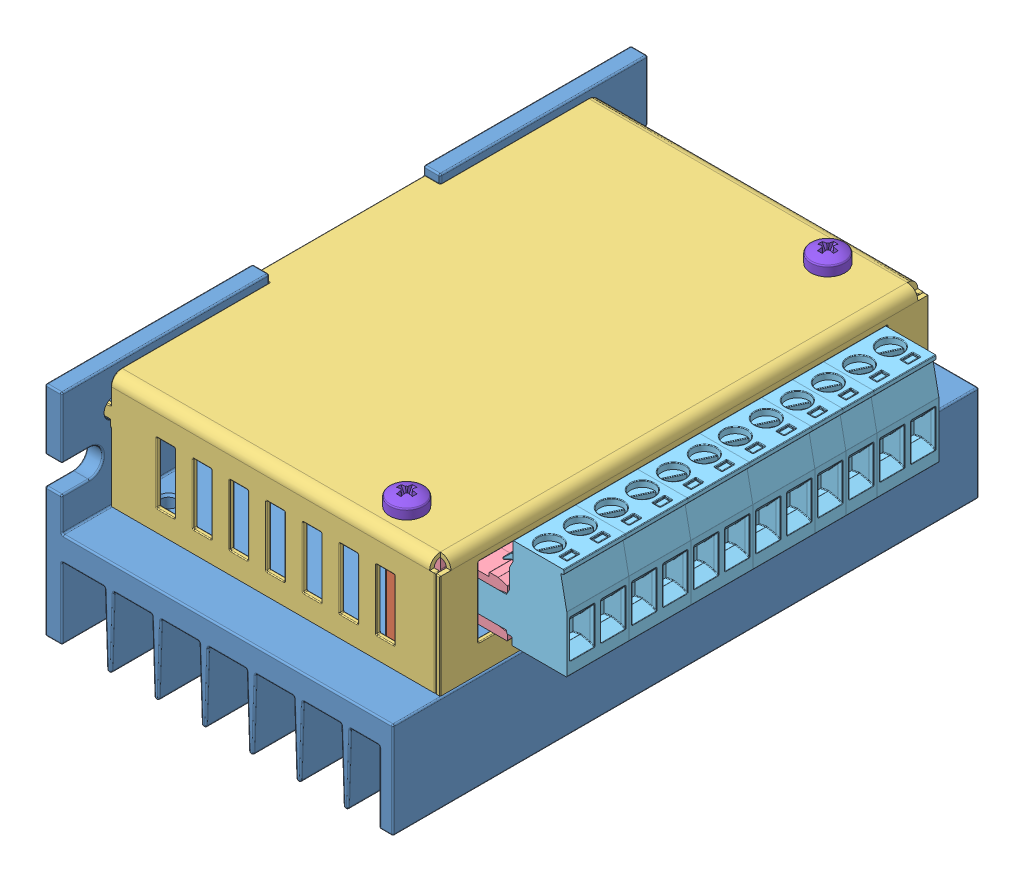
SolidWorks assembly TB6600, configuration Default. Lengths in mm.
Overall size (70.98 37.35 96).
12 component instances, 8 part files, 33 mates.
Components (placement in the parent):
- TB6600 Sink-1: TB6600 Sink [Default] at origin size (57 35.75 96)
- Distance-1: Distance [M3x18] at (43 0 -34.5) size (5 24 4.5)
- Distance-2: Distance [M3x18] at (43 0 34.5) size (5 24 4.5)
- TB6600 Cover-1: TB6600 Cover [Default] at (0 18.75 0) size (56.5 19.75 80)
- Header 200mil-1: Header 200mil [N12] at (48.5 6.85 30.96) size (12 12.2 60.96)
- Plug 200mil-2: Plug 200mil [N2] at (62.83 10.65 25.88) x (-1 0 0) z (0 0 -1) size (18.2 15 10.16)
- Plug 200mil-3: Plug 200mil [N4] at (62.83 10.65 5.56) x (-1 0 0) z (0 0 -1) size (18.2 15 20.32)
- Plug 200mil-4: Plug 200mil [N6] at (62.83 10.65 -24.92) x (-1 0 0) z (0 0 -1) size (18.2 15 30.48)
- LED 3mm Double Stand-1: LED 3mm Double Stand [Default] at (45 5.84 -31) size (11.75 10.16 4.5)
- a6fr-6101-1: a6fr-6101 [Default] at (36.4 6.2 -36.5) x (-1 0 0) z (0 0 -1) size (16.8 13.4 9.9)
- pan head cross recess screw_iso-1: pan head cross recess screw_iso [ISO 7045 - M3 x 4 - Z - 4C] at (43 21.15 -34.5) x (0 -1 0) z (0 0 -1) size (6.35 5.6 5.6)
- pan head cross recess screw_iso-2: pan head cross recess screw_iso [ISO 7045 - M3 x 4 - Z - 4C] at (43 21.15 34.5) x (0 -1 0) z (0 0 -1) size (6.35 5.6 5.6)
Mates (geometry in assembly coordinates):
- Concentric1: concentric aligned: cylinder of TB6600 Sink-1 through (43 0 -34.5) axis (0 1 0) radius 1.25; cylinder of Distance-1 through (43 -6 -34.5) axis (0 1 0) radius 1.5
- Concentric2: concentric aligned: cylinder of TB6600 Sink-1 through (43 0 34.5) axis (0 1 0) radius 1.25; cylinder of Distance-2 through (43 -6 34.5) axis (0 1 0) radius 1.5
- Coincident1: coincident anti-aligned: plane of TB6600 Sink-1 through (0.25 0 48) normal (0 1 0); plane of Distance-1 through (43 0 -34.5) normal (0 -1 0)
- Coincident2: coincident anti-aligned: plane of TB6600 Sink-1 through (0.25 0 48) normal (0 1 0); plane of Distance-2 through (43 0 34.5) normal (0 -1 0)
- Parallel1: parallel aligned: plane of TB6600 Sink-1 through (0 0 0) normal (1 0 0); plane of Distance-1 through (43 0 -34.5) normal (1 0 0)
- Parallel2: parallel aligned: plane of TB6600 Sink-1 through (0 0 0) normal (1 0 0); plane of Distance-2 through (43 0 34.5) normal (1 0 0)
- Concentric3: concentric aligned: cylinder of Distance-2 through (43 18 34.5) axis (0 1 0) radius 1.25; cylinder of TB6600 Cover-1 through (43 18.75 34.5) axis (0 1 0) radius 1.5
- Concentric4: concentric aligned: cylinder of Distance-1 through (43 18 -34.5) axis (0 1 0) radius 1.25; cylinder of TB6600 Cover-1 through (43 18.75 -34.5) axis (0 1 0) radius 1.5
- Coincident3: coincident anti-aligned: plane of Distance-1 through (43 18 -34.5) normal (0 1 0); plane of TB6600 Cover-1 through (53.25 18 40) normal (0 -1 0)
- Concentric5: concentric aligned: cylinder of TB6600 Cover-1 through (43 18.75 -34.5) axis (0 1 0) radius 1.5; cylinder of pan head cross recess screw_iso-1 through (43 46.55 -34.5) axis (0 1 0) radius 1.5
- Concentric6: concentric aligned: cylinder of TB6600 Cover-1 through (43 18.75 34.5) axis (0 1 0) radius 1.5; cylinder of pan head cross recess screw_iso-2 through (43 46.55 34.5) axis (0 1 0) radius 1.5
- Coincident4: coincident anti-aligned: plane of TB6600 Cover-1 through (53.25 18.75 40) normal (0 1 0); plane of pan head cross recess screw_iso-1 through (41.5 18.75 -34.5) normal (0 -1 0)
- Coincident5: coincident anti-aligned: plane of TB6600 Cover-1 through (53.25 18.75 40) normal (0 1 0); plane of pan head cross recess screw_iso-2 through (41.5 18.75 34.5) normal (0 -1 0)
- Parallel3: parallel anti-aligned: plane of TB6600 Sink-1 through (0 0 0) normal (1 0 0); plane of pan head cross recess screw_iso-1 through (43 21.15 -34.5) normal (-1 0 0)
- Parallel4: parallel anti-aligned: plane of TB6600 Sink-1 through (0 0 0) normal (1 0 0); plane of pan head cross recess screw_iso-2 through (43 21.15 34.5) normal (-1 0 0)
- Distance1: distance = 14.5 mm aligned: plane of TB6600 Sink-1 through (0.25 0 48) normal (0 1 0); plane of Header 200mil-1 through (55.5 14.5 28.42) normal (0 1 0)
- Distance2: distance = 14.5 mm aligned: plane of TB6600 Sink-1 through (-0.25 19.75 48) normal (0 0 1); plane of Header 200mil-1 through (48.5 6.85 33.5) normal (0 0 1)
- Distance3: distance = 4.25 mm aligned: plane of TB6600 Sink-1 through (54.25 -0.25 48) normal (1 0 0); plane of Header 200mil-1 through (58.5 6.85 28.42) normal (1 0 0)
- Concentric7: concentric anti-aligned: cylinder of Header 200mil-1 through (49.75 10.65 25.88) axis (1 0 0) radius 1.5; cylinder of Plug 200mil-2 through (51.78 10.65 25.88) axis (-1 0 0) radius 1.5
- Concentric8: concentric anti-aligned: cylinder of Header 200mil-1 through (49.75 10.65 30.96) axis (1 0 0) radius 1.5; cylinder of Plug 200mil-2 through (51.78 10.65 30.96) axis (-1 0 0) radius 1.5
- Concentric9: concentric anti-aligned: cylinder of Header 200mil-1 through (49.75 10.65 20.8) axis (1 0 0) radius 1.5; cylinder of Plug 200mil-3 through (51.78 10.65 20.8) axis (-1 0 0) radius 1.5
- Concentric10: concentric anti-aligned: cylinder of Header 200mil-1 through (49.75 10.65 5.56) axis (1 0 0) radius 1.5; cylinder of Plug 200mil-3 through (51.78 10.65 5.56) axis (-1 0 0) radius 1.5
- Concentric11: concentric anti-aligned: cylinder of Header 200mil-1 through (49.75 10.65 -24.92) axis (1 0 0) radius 1.5; cylinder of Plug 200mil-4 through (51.78 10.65 -24.92) axis (-1 0 0) radius 1.5
- Concentric12: concentric anti-aligned: cylinder of Header 200mil-1 through (49.75 10.65 0.48) axis (1 0 0) radius 1.5; cylinder of Plug 200mil-4 through (51.78 10.65 0.48) axis (-1 0 0) radius 1.5
- Tangent1: tangent anti-aligned: cylinder of Header 200mil-1 through (58.4 13.7347 28.42) axis (0 0 1) radius 0.1; plane of Plug 200mil-2 through (58.33 13.4 23.34) normal (-0.876216 0.481919 0)
- Tangent2: tangent anti-aligned: cylinder of Header 200mil-1 through (58.4 13.7347 18.26) axis (0 0 1) radius 0.1; plane of Plug 200mil-3 through (58.33 13.4 18.26) normal (-0.876216 0.481919 0)
- Tangent3: tangent anti-aligned: cylinder of Header 200mil-1 through (58.4 13.7347 -2.06) axis (0 0 1) radius 0.1; plane of Plug 200mil-4 through (58.33 13.4 -2.06) normal (-0.876216 0.481919 0)
- Coincident6: coincident anti-aligned: plane of TB6600 Cover-1 through (-2.501 16 33.75) normal (0 -1 0); plane of LED 3mm Double Stand-1 through (54 16 -28.75) normal (0 1 0)
- Coincident7: coincident aligned: plane of TB6600 Cover-1 through (54 18.75 0) normal (1 0 0); plane of LED 3mm Double Stand-1 through (54 16 -28.75) normal (1 0 0)
- Coincident8: coincident anti-aligned: plane of TB6600 Cover-1 through (-2.501 16 -33.25) normal (0 0 1); plane of LED 3mm Double Stand-1 through (45 5.84 -33.25) normal (0 0 -1)
- Distance4: distance = 6 mm anti-aligned: plane of a6fr-6101-1 through (19.6 6 -28.25) normal (0 -1 0); plane of TB6600 Sink-1 through (0.25 0 48) normal (0 1 0)
- Distance5: distance = 39.15 mm anti-aligned: plane of a6fr-6101-1 through (36.4 15.375 -35.675) normal (1 0 0); plane of TB6600 Sink-1 through (-2.75 -15.5 48) normal (-1 0 0)
- Distance6: distance = 11.5 mm aligned: plane of TB6600 Sink-1 through (-0.25 19.75 -48) normal (0 0 -1); plane of a6fr-6101-1 through (19.6 15.375 -36.5) normal (0 0 -1)
